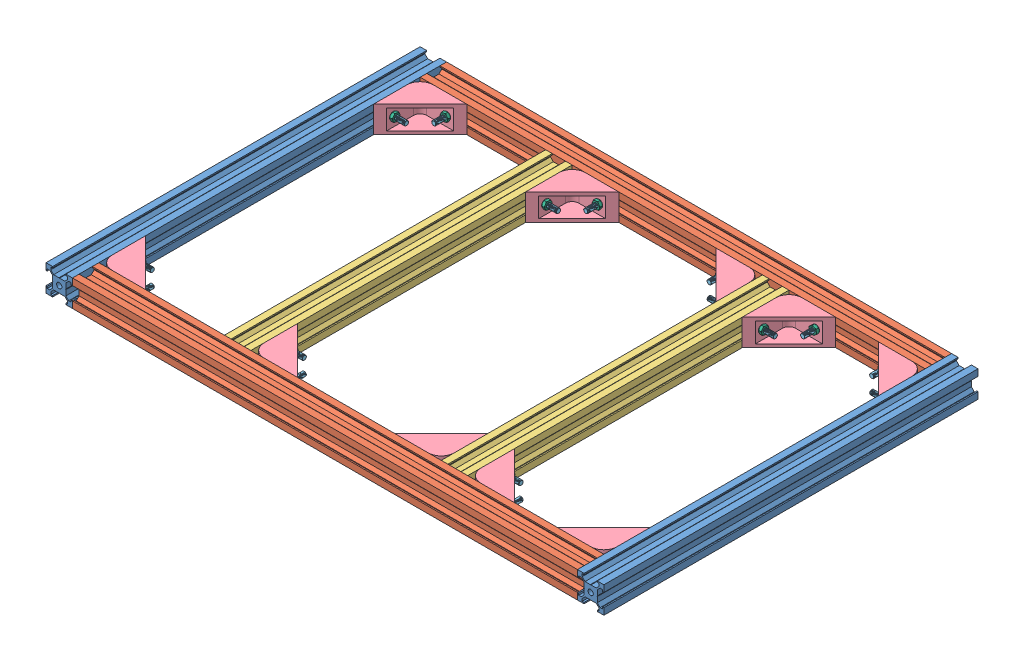
SolidWorks assembly Top Frame, configuration Default. Lengths in mm.
Overall size (422 20 283).
66 component instances, 6 part files, 66 mates.
Components (placement in the parent):
- T-slot aluminium profiles(283)-2: T-slot aluminium profiles(283) [Default] at (139.2356 156.3375 52.1184) size (20 20 283)
- T-slot aluminium profiles(382)-2: T-slot aluminium profiles(382) [Default] at (531.2356 156.3375 325.1184) x (0 0 1) z (-1 0 0) size (20 20 382)
- T-slot aluminium profiles(382)-3: T-slot aluminium profiles(382) [Default] at (531.2356 156.3375 62.1184) x (0 0 1) z (-1 0 0) size (20 20 382)
- T-slot aluminium profiles(283)-3: T-slot aluminium profiles(283) [Default] at (541.2356 156.3375 52.1184) size (20 20 283)
- T-slot aluminium profiles(243)-1: T-slot aluminium profiles(243) [Default] at (418.2356 156.3375 72.1184) size (20 20 243)
- T-slot aluminium profiles(243)-2: T-slot aluminium profiles(243) [Default] at (254.2356 156.3375 72.1184) size (20 20 243)
- Connector and Nut-1: Connector and Nut [Default] at (495.0014 140.4658 271.3786) size (38.1 20 38.1) (flexible)
  - connector-1: connector [Default] at (36.2342 15.8717 43.7398) size (35.36 20 35.36)
  - T-bolt-1: T-bolt [Default] at (38.0779 15.8717 18.3844) x (-1 0 0) z (0 0 -1) size (17.8 12.7 9.5)
  - hexagon nut style 1_is-2: hexagon nut style 1_is [IS 1364-3 - M3-W-N] at (28.8342 15.8717 18.3844) x (0 0.996107 0.088148) z (-1 0 0) size (5.5 6.35 2.4)
  - T-bolt-2: T-bolt [Default] at (10.8788 15.8717 45.5835) x (0 0 -1) z (1 0 0) size (17.8 12.7 9.5)
  - hexagon nut style 1_is-3: hexagon nut style 1_is [IS 1364-3 - M3-W-N] at (10.8788 15.8717 36.3398) x (0.175203 0.984532 0) z (0 0 -1) size (5.5 6.35 2.4)
- Connector and Nut-2: Connector and Nut [Default] at (487.4958 140.4658 108.3525) x (0 0 -1) z (1 0 0) size (38.1 20 38.1) (flexible)
  - connector-1: connector [Default] at (36.2342 15.8717 43.7398) size (35.36 20 35.36)
  - T-bolt-1: T-bolt [Default] at (38.0779 15.8717 18.3844) x (-1 0 0) z (0 0 -1) size (17.8 12.7 9.5)
  - hexagon nut style 1_is-2: hexagon nut style 1_is [IS 1364-3 - M3-W-N] at (28.8342 15.8717 18.3844) x (0 0.922855 0.385148) z (-1 0 0) size (5.5 6.35 2.4)
  - T-bolt-2: T-bolt [Default] at (10.8788 15.8717 45.5835) x (0 0 -1) z (1 0 0) size (17.8 12.7 9.5)
  - hexagon nut style 1_is-3: hexagon nut style 1_is [IS 1364-3 - M3-W-N] at (10.8788 15.8717 36.3398) x (0.207562 0.978222 0) z (0 0 -1) size (5.5 6.35 2.4)
- Connector and Nut-3: Connector and Nut [Default] at (372.0014 140.4658 271.3786) size (38.1 20 38.1) (flexible)
  - connector-1: connector [Default] at (36.2342 15.8717 43.7398) size (35.36 20 35.36)
  - T-bolt-1: T-bolt [Default] at (38.0779 15.8717 18.3844) x (-1 0 0) z (0 0 -1) size (17.8 12.7 9.5)
  - hexagon nut style 1_is-2: hexagon nut style 1_is [IS 1364-3 - M3-W-N] at (28.8342 15.8717 18.3844) x (0 0.996107 0.088148) z (-1 0 0) size (5.5 6.35 2.4)
  - T-bolt-2: T-bolt [Default] at (10.8788 15.8717 45.5835) x (0 0 -1) z (1 0 0) size (17.8 12.7 9.5)
  - hexagon nut style 1_is-3: hexagon nut style 1_is [IS 1364-3 - M3-W-N] at (10.8788 15.8717 36.3398) x (0.175203 0.984532 0) z (0 0 -1) size (5.5 6.35 2.4)
- Connector and Nut-4: Connector and Nut [Default] at (471.9754 140.4658 278.8842) x (0 0 1) z (-1 0 0) size (38.1 20 38.1) (flexible)
  - connector-1: connector [Default] at (36.2342 15.8717 43.7398) size (35.36 20 35.36)
  - T-bolt-1: T-bolt [Default] at (38.0779 15.8717 18.3844) x (-1 0 0) z (0 0 -1) size (17.8 12.7 9.5)
  - hexagon nut style 1_is-2: hexagon nut style 1_is [IS 1364-3 - M3-W-N] at (28.8342 15.8717 18.3844) x (0 0.996107 0.088148) z (-1 0 0) size (5.5 6.35 2.4)
  - T-bolt-2: T-bolt [Default] at (10.8788 15.8717 45.5835) x (0 0 -1) z (1 0 0) size (17.8 12.7 9.5)
  - hexagon nut style 1_is-3: hexagon nut style 1_is [IS 1364-3 - M3-W-N] at (10.8788 15.8717 36.3398) x (0.175203 0.984532 0) z (0 0 -1) size (5.5 6.35 2.4)
- Connector and Nut-5: Connector and Nut [Default] at (192.9754 140.4658 278.8842) x (0 0 1) z (-1 0 0) size (38.1 20 38.1) (flexible)
  - connector-1: connector [Default] at (36.2342 15.8717 43.7398) size (35.36 20 35.36)
  - T-bolt-1: T-bolt [Default] at (38.0779 15.8717 18.3844) x (-1 0 0) z (0 0 -1) size (17.8 12.7 9.5)
  - hexagon nut style 1_is-2: hexagon nut style 1_is [IS 1364-3 - M3-W-N] at (28.8342 15.8717 18.3844) x (0 0.996107 0.088148) z (-1 0 0) size (5.5 6.35 2.4)
  - T-bolt-2: T-bolt [Default] at (10.8788 15.8717 45.5835) x (0 0 -1) z (1 0 0) size (17.8 12.7 9.5)
  - hexagon nut style 1_is-3: hexagon nut style 1_is [IS 1364-3 - M3-W-N] at (10.8788 15.8717 36.3398) x (0.175203 0.984532 0) z (0 0 -1) size (5.5 6.35 2.4)
- Connector and Nut-6: Connector and Nut [Default] at (364.4958 140.4658 108.3525) x (0 0 -1) z (1 0 0) size (38.1 20 38.1) (flexible)
  - connector-1: connector [Default] at (36.2342 15.8717 43.7398) size (35.36 20 35.36)
  - T-bolt-1: T-bolt [Default] at (38.0779 15.8717 18.3844) x (-1 0 0) z (0 0 -1) size (17.8 12.7 9.5)
  - hexagon nut style 1_is-2: hexagon nut style 1_is [IS 1364-3 - M3-W-N] at (28.8342 15.8717 18.3844) x (0 0.996107 0.088148) z (-1 0 0) size (5.5 6.35 2.4)
  - T-bolt-2: T-bolt [Default] at (10.8788 15.8717 45.5835) x (0 0 -1) z (1 0 0) size (17.8 12.7 9.5)
  - hexagon nut style 1_is-3: hexagon nut style 1_is [IS 1364-3 - M3-W-N] at (10.8788 15.8717 36.3398) x (0.175203 0.984532 0) z (0 0 -1) size (5.5 6.35 2.4)
- Connector and Nut-7: Connector and Nut [Default] at (464.4698 140.4658 115.8582) x (-1 0 0) z (0 0 -1) size (38.1 20 38.1) (flexible)
  - connector-1: connector [Default] at (36.2342 15.8717 43.7398) size (35.36 20 35.36)
  - T-bolt-1: T-bolt [Default] at (38.0779 15.8717 18.3844) x (-1 0 0) z (0 0 -1) size (17.8 12.7 9.5)
  - hexagon nut style 1_is-2: hexagon nut style 1_is [IS 1364-3 - M3-W-N] at (28.8342 15.8717 18.3844) x (0 0.978877 0.204449) z (-1 0 0) size (5.5 6.35 2.4)
  - T-bolt-2: T-bolt [Default] at (10.8788 15.8717 45.5835) x (0 0 -1) z (1 0 0) size (17.8 12.7 9.5)
  - hexagon nut style 1_is-3: hexagon nut style 1_is [IS 1364-3 - M3-W-N] at (10.8788 15.8717 36.3398) x (0.629667 0.776865 0) z (0 0 -1) size (5.5 6.35 2.4)
- Connector and Nut-8: Connector and Nut [Default] at (185.4698 140.4658 115.8582) x (-1 0 0) z (0 0 -1) size (38.1 20 38.1) (flexible)
  - connector-1: connector [Default] at (36.2342 15.8717 43.7398) size (35.36 20 35.36)
  - T-bolt-1: T-bolt [Default] at (38.0779 15.8717 18.3844) x (-1 0 0) z (0 0 -1) size (17.8 12.7 9.5)
  - hexagon nut style 1_is-2: hexagon nut style 1_is [IS 1364-3 - M3-W-N] at (28.8342 15.8717 18.3844) x (0 0.646881 -0.762591) z (-1 0 0) size (5.5 6.35 2.4)
  - T-bolt-2: T-bolt [Default] at (10.8788 15.8717 45.5835) x (0 0 -1) z (1 0 0) size (17.8 12.7 9.5)
  - hexagon nut style 1_is-3: hexagon nut style 1_is [IS 1364-3 - M3-W-N] at (10.8788 15.8717 36.3398) x (0.175203 0.984532 0) z (0 0 -1) size (5.5 6.35 2.4)
- Connector and Nut-9: Connector and Nut [Default] at (307.9754 140.4658 278.8842) x (0 0 1) z (-1 0 0) size (38.1 20 38.1) (flexible)
  - connector-1: connector [Default] at (36.2342 15.8717 43.7398) size (35.36 20 35.36)
  - T-bolt-1: T-bolt [Default] at (38.0779 15.8717 18.3844) x (-1 0 0) z (0 0 -1) size (17.8 12.7 9.5)
  - hexagon nut style 1_is-2: hexagon nut style 1_is [IS 1364-3 - M3-W-N] at (28.8342 15.8717 18.3844) x (0 0.977522 0.210833) z (-1 0 0) size (5.5 6.35 2.4)
  - T-bolt-2: T-bolt [Default] at (10.8788 15.8717 45.5835) x (0 0 -1) z (1 0 0) size (17.8 12.7 9.5)
  - hexagon nut style 1_is-3: hexagon nut style 1_is [IS 1364-3 - M3-W-N] at (10.8788 15.8717 36.3398) x (0.179382 0.98378 0) z (0 0 -1) size (5.5 6.35 2.4)
- Connector and Nut-10: Connector and Nut [Default] at (300.4698 140.4658 115.8582) x (-1 0 0) z (0 0 -1) size (38.1 20 38.1) (flexible)
  - connector-1: connector [Default] at (36.2342 15.8717 43.7398) size (35.36 20 35.36)
  - T-bolt-1: T-bolt [Default] at (38.0779 15.8717 18.3844) x (-1 0 0) z (0 0 -1) size (17.8 12.7 9.5)
  - hexagon nut style 1_is-2: hexagon nut style 1_is [IS 1364-3 - M3-W-N] at (28.8342 15.8717 18.3844) x (0 0.997259 0.073993) z (-1 0 0) size (5.5 6.35 2.4)
  - T-bolt-2: T-bolt [Default] at (10.8788 15.8717 45.5835) x (0 0 -1) z (1 0 0) size (17.8 12.7 9.5)
  - hexagon nut style 1_is-3: hexagon nut style 1_is [IS 1364-3 - M3-W-N] at (10.8788 15.8717 36.3398) x (0.103111 0.99467 0) z (0 0 -1) size (5.5 6.35 2.4)
Mates (geometry in assembly coordinates):
- Coincident1: coincident: plane of T-slot aluminium profiles(283)-2 through (149.2356 156.3375 335.1184) normal (1 0 0); plane of T-slot aluminium profiles(382)-2 through (149.2356 156.3375 325.1184) normal (-1 0 0)
- Coincident2: coincident: plane of T-slot aluminium profiles(283)-2 through (139.2356 166.3375 335.1184) normal (0 1 0); plane of T-slot aluminium profiles(382)-2 through (149.2356 166.3375 325.1184) normal (0 1 0)
- Coincident3: coincident: plane of T-slot aluminium profiles(283)-2 through (139.2356 156.3375 335.1184) normal (0 0 1); plane of T-slot aluminium profiles(382)-2 through (149.2356 156.3375 335.1184) normal (0 0 1)
- Coincident4: coincident: plane of T-slot aluminium profiles(283)-2 through (149.2356 156.3375 335.1184) normal (1 0 0); plane of T-slot aluminium profiles(382)-3 through (149.2356 156.3375 62.1184) normal (-1 0 0)
- Coincident5: coincident: plane of T-slot aluminium profiles(283)-2 through (139.2356 166.3375 335.1184) normal (0 1 0); plane of T-slot aluminium profiles(382)-3 through (149.2356 166.3375 62.1184) normal (0 1 0)
- Coincident6: coincident: plane of T-slot aluminium profiles(283)-2 through (139.2356 156.3375 52.1184) normal (0 0 -1); plane of T-slot aluminium profiles(382)-3 through (149.2356 156.3375 52.1184) normal (0 0 -1)
- Coincident7: coincident: plane of T-slot aluminium profiles(382)-3 through (531.2356 156.3375 62.1184) normal (1 0 0); plane of T-slot aluminium profiles(283)-3 through (531.2356 156.3375 335.1184) normal (-1 0 0)
- Coincident8: coincident: plane of T-slot aluminium profiles(382)-3 through (149.2356 156.3375 52.1184) normal (0 0 -1); plane of T-slot aluminium profiles(283)-3 through (541.2356 156.3375 52.1184) normal (0 0 -1)
- Coincident9: coincident: plane of T-slot aluminium profiles(382)-3 through (149.2356 166.3375 62.1184) normal (0 1 0); plane of T-slot aluminium profiles(283)-3 through (541.2356 166.3375 335.1184) normal (0 1 0)
- Coincident11: coincident: plane of T-slot aluminium profiles(382)-2 through (149.2356 166.3375 325.1184) normal (0 1 0); plane of T-slot aluminium profiles(243)-1 through (418.2356 166.3375 315.1184) normal (0 1 0)
- Coincident12: coincident: plane of T-slot aluminium profiles(382)-2 through (149.2356 156.3375 315.1184) normal (0 0 -1); plane of T-slot aluminium profiles(243)-1 through (418.2356 156.3375 315.1184) normal (0 0 1)
- Coincident13: coincident: plane of T-slot aluminium profiles(382)-2 through (149.2356 156.3375 315.1184) normal (0 0 -1); plane of T-slot aluminium profiles(243)-2 through (254.2356 156.3375 315.1184) normal (0 0 1)
- Coincident14: coincident: plane of T-slot aluminium profiles(382)-2 through (149.2356 166.3375 325.1184) normal (0 1 0); plane of T-slot aluminium profiles(243)-2 through (254.2356 166.3375 315.1184) normal (0 1 0)
- Distance1: distance = 95 mm: plane of T-slot aluminium profiles(243)-2 through (244.2356 156.3375 315.1184) normal (-1 0 0); plane of T-slot aluminium profiles(283)-2 through (149.2356 156.3375 335.1184) normal (1 0 0)
- Coincident18: coincident: plane of T-slot aluminium profiles(283)-3 through (532.1793 156.3375 335.1184) normal (1 0 0); plane of Connector and Nut-1/T-bolt-1 through (532.1793 149.9875 285.013) normal (-1 0 0)
- Coincident19: coincident: plane of T-slot aluminium profiles(283)-3 through (541.2356 166.3375 335.1184) normal (0 1 0); plane of Connector and Nut-1/connector-1 through (531.2356 166.3375 315.1184) normal (0 1 0)
- Coincident20: coincident: plane of T-slot aluminium profiles(382)-2 through (149.2356 156.3375 316.0621) normal (0 0 1); plane of Connector and Nut-1/T-bolt-2 through (510.6302 149.9875 316.0621) normal (0 0 -1)
- Coincident22: coincident: plane of T-slot aluminium profiles(382)-2 through (149.2356 156.3375 315.1184) normal (0 0 -1); plane of Connector and Nut-1/connector-1 through (495.8802 166.3375 315.1184) normal (0 0 1)
- Coincident23: coincident: plane of T-slot aluminium profiles(283)-3 through (531.2356 156.3375 335.1184) normal (-1 0 0); plane of Connector and Nut-1/connector-1 through (531.2356 166.3375 315.1184) normal (1 0 0)
- Coincident24: coincident: plane of T-slot aluminium profiles(283)-3 through (532.1793 156.3375 335.1184) normal (1 0 0); plane of Connector and Nut-2/T-bolt-2 through (532.1793 149.9875 92.7237) normal (-1 0 0)
- Coincident25: coincident: plane of T-slot aluminium profiles(283)-3 through (541.2356 166.3375 335.1184) normal (0 1 0); plane of Connector and Nut-2/connector-1 through (531.2356 166.3375 72.1184) normal (0 1 0)
- Coincident26: coincident: plane of T-slot aluminium profiles(382)-3 through (149.2356 156.3375 71.1746) normal (0 0 -1); plane of Connector and Nut-2/T-bolt-1 through (501.1302 149.9875 71.1746) normal (0 0 1)
- Coincident27: coincident: plane of T-slot aluminium profiles(283)-3 through (531.2356 156.3375 335.1184) normal (-1 0 0); plane of Connector and Nut-2/connector-1 through (531.2356 166.3375 107.4737) normal (1 0 0)
- Coincident28: coincident: plane of T-slot aluminium profiles(382)-3 through (149.2356 156.3375 72.1184) normal (0 0 1); plane of Connector and Nut-2/connector-1 through (531.2356 166.3375 72.1184) normal (0 0 -1)
- Coincident29: coincident: plane of T-slot aluminium profiles(243)-1 through (409.1793 156.3375 315.1184) normal (1 0 0); plane of Connector and Nut-3/T-bolt-1 through (409.1793 149.9875 285.013) normal (-1 0 0)
- Coincident30: coincident: plane of T-slot aluminium profiles(382)-2 through (149.2356 156.3375 316.0621) normal (0 0 1); plane of Connector and Nut-3/T-bolt-2 through (387.6302 149.9875 316.0621) normal (0 0 -1)
- Coincident31: coincident: plane of T-slot aluminium profiles(382)-2 through (149.2356 166.3375 325.1184) normal (0 1 0); plane of Connector and Nut-3/connector-1 through (408.2356 166.3375 315.1184) normal (0 1 0)
- Coincident32: coincident: plane of T-slot aluminium profiles(382)-2 through (149.2356 156.3375 315.1184) normal (0 0 -1); plane of Connector and Nut-3/connector-1 through (372.8802 166.3375 315.1184) normal (0 0 1)
- Coincident33: coincident: plane of T-slot aluminium profiles(243)-1 through (408.2356 156.3375 315.1184) normal (-1 0 0); plane of Connector and Nut-3/connector-1 through (408.2356 166.3375 315.1184) normal (1 0 0)
- Coincident39: coincident: plane of T-slot aluminium profiles(283)-2 through (139.2356 166.3375 335.1184) normal (0 1 0); plane of Connector and Nut-5/connector-1 through (149.2356 166.3375 315.1184) normal (0 1 0)
- Coincident40: coincident: plane of T-slot aluminium profiles(283)-2 through (149.2356 156.3375 335.1184) normal (1 0 0); plane of Connector and Nut-5/connector-1 through (149.2356 166.3375 279.763) normal (-1 0 0)
- Coincident42: coincident: plane of T-slot aluminium profiles(283)-2 through (148.2918 156.3375 335.1184) normal (-1 0 0); plane of Connector and Nut-5/T-bolt-2 through (148.2918 149.9875 294.513) normal (1 0 0)
- Coincident43: coincident: plane of T-slot aluminium profiles(382)-2 through (149.2356 156.3375 316.0621) normal (0 0 1); plane of Connector and Nut-5/T-bolt-1 through (179.3409 149.9875 316.0621) normal (0 0 -1)
- Coincident44: coincident: plane of T-slot aluminium profiles(382)-2 through (149.2356 156.3375 315.1184) normal (0 0 -1); plane of Connector and Nut-5/connector-1 through (149.2356 166.3375 315.1184) normal (0 0 1)
- Coincident45: coincident: plane of T-slot aluminium profiles(243)-1 through (408.2356 156.3375 315.1184) normal (-1 0 0); plane of Connector and Nut-6/connector-1 through (408.2356 166.3375 107.4737) normal (1 0 0)
- Coincident46: coincident: plane of T-slot aluminium profiles(243)-1 through (418.2356 166.3375 315.1184) normal (0 1 0); plane of Connector and Nut-6/connector-1 through (408.2356 166.3375 72.1184) normal (0 1 0)
- Coincident47: coincident: plane of T-slot aluminium profiles(243)-1 through (409.1793 156.3375 315.1184) normal (1 0 0); plane of Connector and Nut-6/T-bolt-2 through (409.1793 149.9875 92.7237) normal (-1 0 0)
- Coincident48: coincident: plane of T-slot aluminium profiles(382)-3 through (149.2356 156.3375 71.1746) normal (0 0 -1); plane of Connector and Nut-6/T-bolt-1 through (378.1302 149.9875 71.1746) normal (0 0 1)
- Coincident50: coincident: plane of T-slot aluminium profiles(382)-3 through (149.2356 166.3375 62.1184) normal (0 1 0); plane of Connector and Nut-6/connector-1 through (408.2356 166.3375 72.1184) normal (0 1 0)
- Coincident51: coincident: plane of T-slot aluminium profiles(382)-3 through (149.2356 156.3375 72.1184) normal (0 0 1); plane of Connector and Nut-6/connector-1 through (408.2356 166.3375 72.1184) normal (0 0 -1)
- Coincident57: coincident: plane of T-slot aluminium profiles(283)-2 through (139.2356 166.3375 335.1184) normal (0 1 0); plane of Connector and Nut-8/connector-1 through (149.2356 166.3375 72.1184) normal (0 1 0)
- Coincident58: coincident: plane of T-slot aluminium profiles(283)-2 through (148.2918 156.3375 335.1184) normal (-1 0 0); plane of Connector and Nut-8/T-bolt-1 through (148.2918 149.9875 102.2237) normal (1 0 0)
- Coincident59: coincident: plane of T-slot aluminium profiles(382)-3 through (149.2356 156.3375 71.1746) normal (0 0 -1); plane of Connector and Nut-8/T-bolt-2 through (169.8409 149.9875 71.1746) normal (0 0 1)
- Coincident60: coincident: plane of T-slot aluminium profiles(382)-3 through (149.2356 156.3375 72.1184) normal (0 0 1); plane of Connector and Nut-8/connector-1 through (184.5909 166.3375 72.1184) normal (0 0 -1)
- Coincident61: coincident: plane of T-slot aluminium profiles(283)-2 through (149.2356 156.3375 335.1184) normal (1 0 0); plane of Connector and Nut-8/connector-1 through (149.2356 166.3375 72.1184) normal (-1 0 0)
- Distance2: distance = 103 mm: plane of T-slot aluminium profiles(243)-1 through (428.2356 156.3375 315.1184) normal (1 0 0); plane of T-slot aluminium profiles(283)-3 through (531.2356 156.3375 335.1184) normal (-1 0 0)
- Coincident64: coincident: plane of T-slot aluminium profiles(243)-1 through (427.2918 156.3375 315.1184) normal (-1 0 0); plane of Connector and Nut-7/T-bolt-1 through (427.2918 149.9875 102.2237) normal (1 0 0)
- Coincident65: coincident: plane of T-slot aluminium profiles(382)-3 through (149.2356 156.3375 71.1746) normal (0 0 -1); plane of Connector and Nut-7/T-bolt-2 through (448.8409 149.9875 71.1746) normal (0 0 1)
- Coincident66: coincident: plane of T-slot aluminium profiles(243)-1 through (418.2356 166.3375 315.1184) normal (0 1 0); plane of Connector and Nut-7/connector-1 through (428.2356 166.3375 72.1184) normal (0 1 0)
- Coincident67: coincident: plane of T-slot aluminium profiles(382)-3 through (149.2356 156.3375 72.1184) normal (0 0 1); plane of Connector and Nut-7/connector-1 through (463.5909 166.3375 72.1184) normal (0 0 -1)
- Coincident68: coincident: plane of T-slot aluminium profiles(243)-1 through (428.2356 156.3375 315.1184) normal (1 0 0); plane of Connector and Nut-7/connector-1 through (428.2356 166.3375 72.1184) normal (-1 0 0)
- Coincident69: coincident: plane of T-slot aluminium profiles(382)-2 through (149.2356 156.3375 316.0621) normal (0 0 1); plane of Connector and Nut-4/T-bolt-1 through (458.3409 149.9875 316.0621) normal (0 0 -1)
- Coincident70: coincident: plane of T-slot aluminium profiles(243)-1 through (427.2918 156.3375 315.1184) normal (-1 0 0); plane of Connector and Nut-4/T-bolt-2 through (427.2918 149.9875 294.513) normal (1 0 0)
- Coincident71: coincident: plane of T-slot aluminium profiles(243)-1 through (418.2356 166.3375 315.1184) normal (0 1 0); plane of Connector and Nut-4/connector-1 through (428.2356 166.3375 315.1184) normal (0 1 0)
- Coincident72: coincident: plane of T-slot aluminium profiles(243)-1 through (428.2356 156.3375 315.1184) normal (1 0 0); plane of Connector and Nut-4/connector-1 through (428.2356 166.3375 279.763) normal (-1 0 0)
- Coincident73: coincident: plane of T-slot aluminium profiles(382)-2 through (149.2356 156.3375 315.1184) normal (0 0 -1); plane of Connector and Nut-4/connector-1 through (428.2356 166.3375 315.1184) normal (0 0 1)
- Coincident74: coincident: plane of T-slot aluminium profiles(382)-2 through (149.2356 156.3375 316.0621) normal (0 0 1); plane of Connector and Nut-9/T-bolt-1 through (294.3409 149.9875 316.0621) normal (0 0 -1)
- Coincident75: coincident: plane of T-slot aluminium profiles(243)-2 through (263.2918 156.3375 315.1184) normal (-1 0 0); plane of Connector and Nut-9/T-bolt-2 through (263.2918 149.9875 294.513) normal (1 0 0)
- Coincident76: coincident: plane of T-slot aluminium profiles(243)-2 through (264.2356 156.3375 315.1184) normal (1 0 0); plane of Connector and Nut-9/connector-1 through (264.2356 166.3375 279.763) normal (-1 0 0)
- Coincident77: coincident: plane of T-slot aluminium profiles(382)-2 through (149.2356 156.3375 315.1184) normal (0 0 -1); plane of Connector and Nut-9/connector-1 through (264.2356 166.3375 315.1184) normal (0 0 1)
- Coincident78: coincident: plane of T-slot aluminium profiles(243)-2 through (254.2356 166.3375 315.1184) normal (0 1 0); plane of Connector and Nut-9/connector-1 through (264.2356 166.3375 315.1184) normal (0 1 0)
- Coincident79: coincident: plane of T-slot aluminium profiles(243)-2 through (263.2918 156.3375 315.1184) normal (-1 0 0); plane of Connector and Nut-10/T-bolt-1 through (263.2918 149.9875 102.2237) normal (1 0 0)
- Coincident80: coincident: plane of T-slot aluminium profiles(382)-3 through (149.2356 156.3375 71.1746) normal (0 0 -1); plane of Connector and Nut-10/T-bolt-2 through (284.8409 149.9875 71.1746) normal (0 0 1)
- Coincident81: coincident: plane of T-slot aluminium profiles(243)-2 through (264.2356 156.3375 315.1184) normal (1 0 0); plane of Connector and Nut-10/connector-1 through (264.2356 166.3375 72.1184) normal (-1 0 0)
- Coincident82: coincident: plane of T-slot aluminium profiles(382)-3 through (149.2356 156.3375 72.1184) normal (0 0 1); plane of Connector and Nut-10/connector-1 through (299.5909 166.3375 72.1184) normal (0 0 -1)
- Coincident83: coincident: plane of T-slot aluminium profiles(243)-2 through (254.2356 166.3375 315.1184) normal (0 1 0); plane of Connector and Nut-10/connector-1 through (264.2356 166.3375 72.1184) normal (0 1 0)
